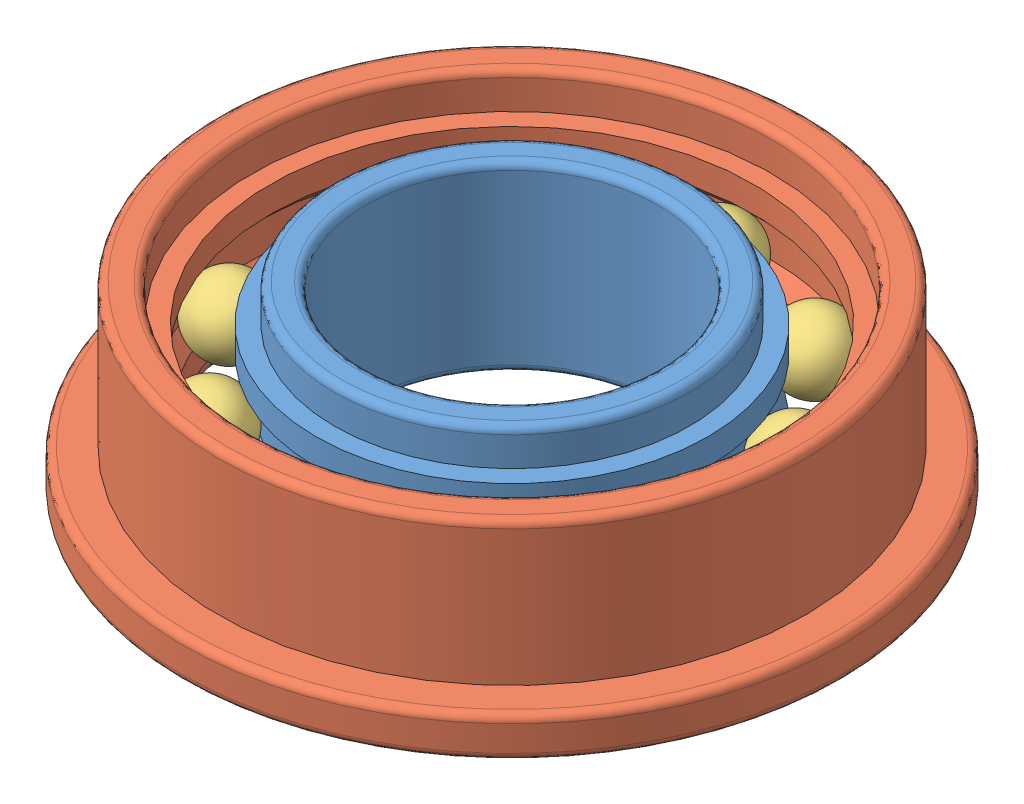
SolidWorks assembly V8_F688ZZ_assemblyURC 2024_V4, configuration Default. Lengths in mm.
Overall size (20.89 5 20.89).
12 component instances, 3 part files, 8 mates.
Components (placement in the parent):
- V8_F688ZZ_shaftURC 2024_V4-1: V8_F688ZZ_shaftURC 2024_V4 [Default] at origin size (10.7 5 10.7)
- V8_F688ZZ_HousingURC 2024_V4-1: V8_F688ZZ_HousingURC 2024_V4 [Default] x (0.984312 0 0.176438) z (-0.176438 0 0.984312) size (18 5 18)
- V8_F688ZZ_BallURC 2024_V4-1: V8_F688ZZ_BallURC 2024_V4 [Default] at (5.5752 2.5 -2.1489) x (0.959238 0.232099 0.161224) z (-0.142462 -0.095558 0.985177) size (2 2 2)
- V8_F688ZZ_BallURC 2024_V4-20: V8_F688ZZ_BallURC 2024_V4 [Default] at (3.2474 2.5 -5.0155) x (0.870805 0.232099 -0.433393) z (0.463818 -0.095558 0.880762) size (2 2 2)
- V8_F688ZZ_BallURC 2024_V4-21: V8_F688ZZ_BallURC 2024_V4 [Default] at (-0.3209 2.5 -5.9664) x (0.449753 0.232099 -0.862469) z (0.892936 -0.095558 0.439926) size (2 2 2)
- V8_F688ZZ_BallURC 2024_V4-22: V8_F688ZZ_BallURC 2024_V4 [Default] at (-3.7665 2.5 -4.6383) x (-0.143088 0.232099 -0.96211) z (0.980982 -0.095558 -0.168947) size (2 2 2)
- V8_F688ZZ_BallURC 2024_V4-23: V8_F688ZZ_BallURC 2024_V4 [Default] at (-5.7735 2.5 -1.5385) x (-0.681275 0.232099 -0.694258) z (0.694326 -0.095558 -0.713288) size (2 2 2)
- V8_F688ZZ_BallURC 2024_V4-24: V8_F688ZZ_BallURC 2024_V4 [Default] at (-5.5752 2.5 2.1489) x (-0.959238 0.232099 -0.161224) z (0.142462 -0.095558 -0.985177) size (2 2 2)
- V8_F688ZZ_BallURC 2024_V4-25: V8_F688ZZ_BallURC 2024_V4 [Default] at (-3.2474 2.5 5.0155) x (-0.870805 0.232099 0.433393) z (-0.463818 -0.095558 -0.880762) size (2 2 2)
- V8_F688ZZ_BallURC 2024_V4-26: V8_F688ZZ_BallURC 2024_V4 [Default] at (0.3209 2.5 5.9664) x (-0.449753 0.232099 0.862469) z (-0.892936 -0.095558 -0.439926) size (2 2 2)
- V8_F688ZZ_BallURC 2024_V4-27: V8_F688ZZ_BallURC 2024_V4 [Default] at (3.7665 2.5 4.6383) x (0.143088 0.232099 0.96211) z (-0.980982 -0.095558 0.168947) size (2 2 2)
- V8_F688ZZ_BallURC 2024_V4-28: V8_F688ZZ_BallURC 2024_V4 [Default] at (5.7735 2.5 1.5385) x (0.681275 0.232099 0.694258) z (-0.694326 -0.095558 0.713288) size (2 2 2)
Mates (geometry in assembly coordinates):
- Eş Merkezli1: concentric aligned: cylinder of F688ZZ_shaft-1 through (0 5 0) axis (0 -1 0) radius 5.35; cylinder of F688ZZ_Housing-1 through (0 5 0) axis (0 -1 0) radius 6.6
- Çakışık2: coincident aligned: plane of F688ZZ_shaft-1 through (0 0 0) normal (0 -1 0); plane of F688ZZ_Housing-1 through (0 0 0) normal (0 -1 0)
- Teğet1: tangent anti-aligned: cylinder of F688ZZ_shaft-1 through (0 0 0) axis (0 -1 0) radius 4.975; sphere of F688ZZ_Ball-1
- Teğet2: tangent anti-aligned: cone of F688ZZ_shaft-1 through (0 1.5 0) axis (0 1 0); sphere of F688ZZ_Ball-1
- Teğet3: tangent anti-aligned: cone of F688ZZ_shaft-1 through (0 2.9142 0) axis (0 -1 0); sphere of F688ZZ_Ball-1
- Teğet4: tangent aligned: cylinder of F688ZZ_Housing-1 through (0 0 0) axis (0 -1 0) radius 6.975; sphere of F688ZZ_Ball-1
- Teğet5: tangent aligned: cone of F688ZZ_Housing-1 through (0 2.0858 0) axis (0 -1 0); sphere of F688ZZ_Ball-1
- Teğet6: tangent aligned: cone of F688ZZ_Housing-1 through (0 4 0) axis (0 1 0); sphere of F688ZZ_Ball-1
